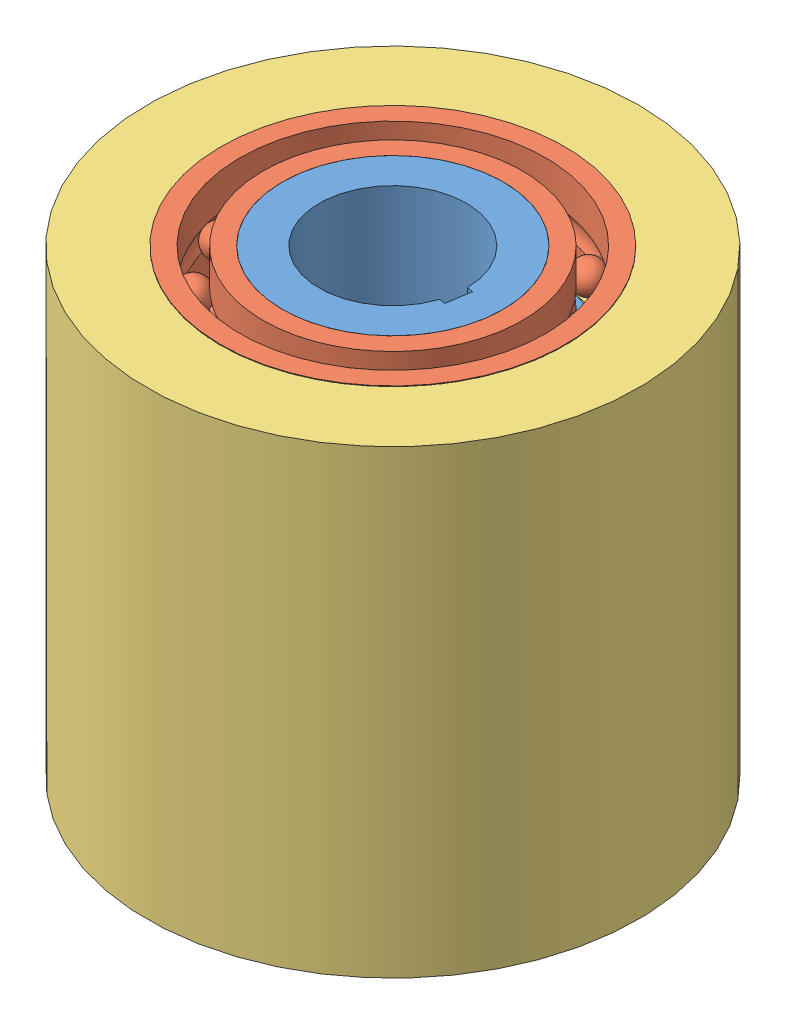
SolidWorks assembly one way bearing assembly 2, configuration Default. Lengths in mm.
Overall size (82.54 75.1 82.54).
4 component instances, 3 part files, 6 mates.
Components (placement in the parent):
- inner race final-1: inner race final [Default] at (27.3509 36.7185 -30.5035) size (50 75 50.74)
- ball bearing-7: ball bearing [Default] at (30.9905 98.5403 12.8822) x (0 -1 0) z (-0.999857 0 0.016919) size (15 56 56)
- ball bearing-8: ball bearing [Default] at (30.9905 38.5403 12.8822) x (0 -1 0) z (-0.399103 0 0.916906) size (15 56 56)
- outer race final-2: outer race final [Default] at (30.0206 68.4419 -17.1022) x (0 1 0) z (0.999477 0 -0.032332) size (75 80 80)
Mates (geometry in assembly coordinates):
- Concentric16: concentric anti-aligned: cylinder of inner race final-1 through (30.9905 106.0403 12.8822) axis (0 -1 0) radius 18; cylinder of ball bearing-7 through (30.9905 1098.5403 12.8822) axis (0 1 0) radius 18
- Coincident7: coincident aligned: circle of inner race final-1; circle of ball bearing-7
- Concentric17: concentric anti-aligned: cylinder of inner race final-1 through (30.9905 106.0403 12.8822) axis (0 -1 0) radius 18; cylinder of ball bearing-8 through (30.9905 1038.5403 12.8822) axis (0 1 0) radius 18
- Coincident8: coincident aligned: circle of inner race final-1; circle of ball bearing-8
- Concentric19: concentric anti-aligned: cylinder of ball bearing-8 through (30.9905 1038.5403 12.8822) axis (0 1 0) radius 28; cylinder of outer race final-2 through (30.9905 -931.5581 12.8822) axis (0 -1 0) radius 28
- Concentric21: concentric anti-aligned: cylinder of ball bearing-7 through (30.9905 1098.5403 12.8822) axis (0 1 0) radius 28; cylinder of outer race final-2 through (30.9905 -931.5581 12.8822) axis (0 -1 0) radius 28
